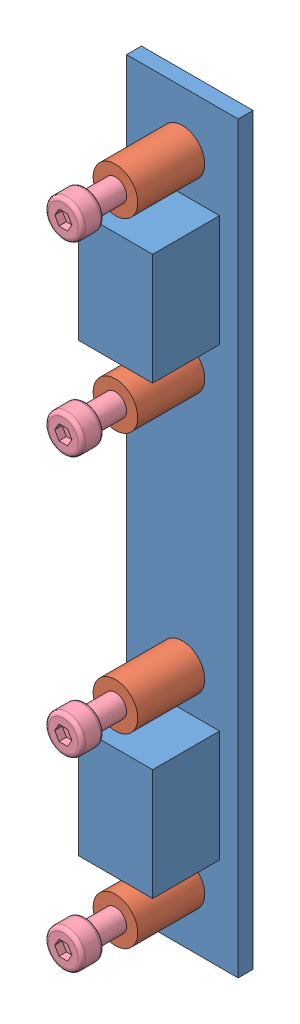
SolidWorks assembly Ensamblaje3, configuration Predeterminado. Lengths in mm.
Overall size (15 100 23).
17 component instances, 4 part files, 8 mates.
Components (placement in the parent):
- PlacaDospuntos-1: PlacaDospuntos [Predeterminado] at (-18.0638 -2.8662 96.5) size (15 100 11)
- Ajuste Display-1: Ajuste Display [Predeterminado] at (-17.3405 39.8638 79.0956) size (6 6 23)
  - Separador-1: Separador [Predeterminado] at (-0.7232 -0.23 17.4044) size (6 6 9)
  - Tuerca M3-1: Tuerca M3 [Predeterminado] at (-0.7232 -0.23 13.4044) x (1 0 0) z (0 -1 0) size (5.77 2 5)
  - Tornillo M3x20_CC-1: Tornillo M3x20_CC [Predeterminado] at (-0.7232 -0.23 10.4144) size (5 5 23)
- Ajuste Display-2: Ajuste Display [Predeterminado] at (-17.3405 14.8638 79.0956) size (6 6 23)
  - Separador-1: Separador [Predeterminado] at (-0.7232 -0.23 17.4044) size (6 6 9)
  - Tuerca M3-1: Tuerca M3 [Predeterminado] at (-0.7232 -0.23 13.4044) x (1 0 0) z (0 -1 0) size (5.77 2 5)
  - Tornillo M3x20_CC-1: Tornillo M3x20_CC [Predeterminado] at (-0.7232 -0.23 10.4144) size (5 5 23)
- Ajuste Display-3: Ajuste Display [Predeterminado] at (-17.3405 -20.1362 79.0956) size (6 6 23)
  - Separador-1: Separador [Predeterminado] at (-0.7232 -0.23 17.4044) size (6 6 9)
  - Tuerca M3-1: Tuerca M3 [Predeterminado] at (-0.7232 -0.23 13.4044) x (1 0 0) z (0 -1 0) size (5.77 2 5)
  - Tornillo M3x20_CC-1: Tornillo M3x20_CC [Predeterminado] at (-0.7232 -0.23 10.4144) size (5 5 23)
- Ajuste Display-4: Ajuste Display [Predeterminado] at (-17.3405 -45.1362 79.0956) size (6 6 23)
  - Separador-1: Separador [Predeterminado] at (-0.7232 -0.23 17.4044) size (6 6 9)
  - Tuerca M3-1: Tuerca M3 [Predeterminado] at (-0.7232 -0.23 13.4044) x (1 0 0) z (0 -1 0) size (5.77 2 5)
  - Tornillo M3x20_CC-1: Tornillo M3x20_CC [Predeterminado] at (-0.7232 -0.23 10.4144) size (5 5 23)
Mates (geometry in assembly coordinates):
- Coincidente1: coincident aligned: plane of Ajuste Display-3/Separador-1 through (-18.0638 -20.3662 105.5) normal (0 0 1); plane of Ajuste Display-4/Separador-1 through (-18.0638 -45.3662 105.5) normal (0 0 1)
- Coincidente2: coincident aligned: plane of Ajuste Display-2/Separador-1 through (-18.0638 14.6338 105.5) normal (0 0 1); plane of Ajuste Display-3/Separador-1 through (-18.0638 -20.3662 105.5) normal (0 0 1)
- Coincidente3: coincident aligned: plane of Ajuste Display-1/Separador-1 through (-18.0638 39.6338 105.5) normal (0 0 1); plane of Ajuste Display-2/Separador-1 through (-18.0638 14.6338 105.5) normal (0 0 1)
- Coincidente4: coincident anti-aligned: plane of PlacaDospuntos-1 through (-18.0638 -2.8662 96.5) normal (0 0 1); plane of Ajuste Display-1/Separador-1 through (-18.0638 39.6338 96.5) normal (0 0 -1)
- Concéntrica1: concentric anti-aligned: cylinder of PlacaDospuntos-1 through (-18.0638 39.6338 94.5) axis (0 0 1) radius 1.25; cylinder of Ajuste Display-1/Separador-1 through (-18.0638 39.6338 105.5) axis (0 0 -1) radius 3
- Concéntrica2: concentric anti-aligned: cylinder of PlacaDospuntos-1 through (-18.0638 14.6338 94.5) axis (0 0 1) radius 1.25; cylinder of Ajuste Display-2/Separador-1 through (-18.0638 14.6338 105.5) axis (0 0 -1) radius 3
- Concéntrica3: concentric anti-aligned: cylinder of PlacaDospuntos-1 through (-18.0638 -20.3662 94.5) axis (0 0 1) radius 1.25; cylinder of Ajuste Display-3/Separador-1 through (-18.0638 -20.3662 105.5) axis (0 0 -1) radius 3
- Concéntrica4: concentric anti-aligned: cylinder of PlacaDospuntos-1 through (-18.0638 -45.3662 94.5) axis (0 0 1) radius 1.25; cylinder of Ajuste Display-4/Separador-1 through (-18.0638 -45.3662 105.5) axis (0 0 -1) radius 3
